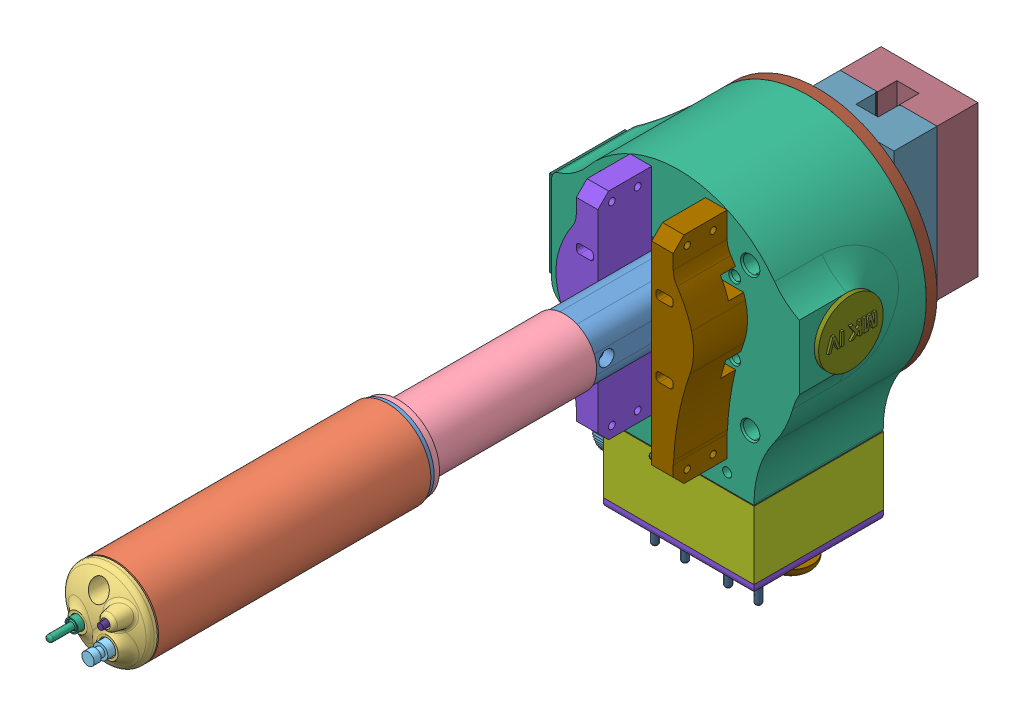
SolidWorks assembly simple_collective, configuration По умолчанию. Lengths in mm.
Overall size (184.78 180.53 404.93).
48 component instances, 32 part files, 9 mates.
Components (placement in the parent):
- collective_base-1: collective_base [По умолчанию] at origin size (122 120.43 169.5)
  - collective_base_lever_connector_cbase010-1: collective_base_lever_connector_cbase010 [По умолчанию] at (44.3103 52.5722 -4.4772) size (25 25 86)
  - 608_bearing_v1-1: 608_bearing_v1 [По умолчанию] at (58.4103 52.5722 5.5228) x (0 -0.975622 0.219457) z (0 0.219457 0.975622) size (22 7.15 22)
  - 608_bearing_v1-2: 608_bearing_v1 [По умолчанию] at (16.3103 52.5722 5.5228) x (0 -1 0) z (0 0 1) size (22 7.15 22)
  - 608_bearing_v1-3: 608_bearing_v1 [По умолчанию] at (72.3103 52.5722 5.5228) x (0 1 0) z (0 0 1) size (22 7.15 22)
  - 608_bearing_v1-4: 608_bearing_v1 [По умолчанию] at (30.2103 52.5722 5.5228) x (0 1 0) z (0 0 1) size (22 7.15 22)
  - M8 washer_regular-1: M8 washer_regular [По умолчанию] at (31.8103 52.5722 5.5228) x (0 0 1) z (-1 0 0) size (15.8 15.8 1.5)
  - M8 washer_regular-2: M8 washer_regular [По умолчанию] at (58.3103 52.5722 5.5228) x (0 0 1) z (-1 0 0) size (15.8 15.8 1.5)
  - collective_base_hinge_frame_p1_cbase007-3: collective_base_hinge_frame_p1_cbase007 [По умолчанию] at (44.3103 52.5722 20.5228) x (1 0 0) z (0 1 0) size (78.5 15 68)
  - M6x70mm-1: M6x70mm [По умолчанию] at (5.4103 52.5722 5.5228) x (0 -0.980406 -0.196989) z (0 -0.196989 0.980406) size (11.6 74.3 11.6)
  - collective_base_housing_p1_cbase001-1: collective_base_housing_p1_cbase001 [По умолчанию] at (44.3103 44.0722 -32.4772) x (0 1 0) z (1 0 0) size (117.43 62.91 115.35)
  - collective_base_hinge_frame_p2_cbase008-2: collective_base_hinge_frame_p2_cbase008 [По умолчанию] at (44.3103 52.5722 -9.4772) x (-1 0 0) z (0 1 0) size (65 15 68)
  - collective_base_friction_tensioner_p2_cbase012-1: collective_base_friction_tensioner_p2_cbase012 [По умолчанию] at (21.8103 44.2222 27.5228) x (1 0 0) z (0 -1 0) size (19.47 25 100)
  - collective_base_friction_tensioner_p1_cbase011-1: collective_base_friction_tensioner_p1_cbase011 [По умолчанию] at (66.8103 44.1222 52.5228) x (-1 0 0) z (0 -1 0) size (19.47 25 100)
  - 6x6x4mm_square-1: 6x6x4mm_square [По умолчанию] at (2.4103 49.5722 5.5228) size (6 6 4)
  - M8 washer_regular-3: M8 washer_regular [По умолчанию] at (72.4103 52.5722 5.5228) x (0 0 -1) z (1 0 0) size (15.8 15.8 1.5)
  - M8 washer_regular-4: M8 washer_regular [По умолчанию] at (75.4103 52.5722 5.5228) x (0 0 1) z (-1 0 0) size (15.8 15.8 1.5)
  - collective_base_housing_p2_cbase002-1: collective_base_housing_p2_cbase002 [По умолчанию] at (44.3103 44.0722 -37.4772) x (0 -1 0) z (-1 0 0) size (110 22.5 110)
  - collective_base_hinge_curtain_cbase009-1: collective_base_hinge_curtain_cbase009 [По умолчанию] at (42.9159 43.7468 -9.4772) x (1 0 0) z (0 0 -1) size (65 54.8 2.4)
  - collective_base_housing_p4_cbase004-1: collective_base_housing_p4_cbase004 [По умолчанию] at (44.3103 44.0722 -88.9772) x (-1 0 0) z (0 1 0) size (45 19 70)
  - collective_base_housing_p3_cbase003-1: collective_base_housing_p3_cbase003 [По умолчанию] at (44.3103 44.0722 -49.9772) x (1 0 0) z (0 1 0) size (45 20 70)
  - collective_base_housing_p5_cbase005-1: collective_base_housing_p5_cbase005 [По умолчанию] at (-10.6795 48.8722 6.7228) x (0 0 -1) z (0 1 0) size (39 8 44)
  - collective_base_housing_p6_cbase006-1: collective_base_housing_p6_cbase006 [По умолчанию] at (96.3205 51.5722 5.5228) x (0 0.9998 0.019984) z (0 0.019984 -0.9998) size (32 7 32)
  - 6x17mm_tact-1: 6x17mm_tact [По умолчанию] at (44.3103 1.0722 -29.5772) x (1 0 0) z (0 0 -1) size (5.8 5.8 16.4)
  - collective_base_pedestal_mockup_cbase013-1: collective_base_pedestal_mockup_cbase013 [По умолчанию] at (44.3103 -18.3542 -2.4772) x (1 0 0) z (0 -1 0) size (72 62 7)
- simple_collective_body-1: simple_collective_body [По умолчанию] at (115.5739 187.1995 -54.6178) x (0.899263 0.322697 -0.295284) z (0.337757 -0.941233 0) size (114.48 229.77 53.21)
  - simple_collective_throttle_frame_part1_slbody02-1: simple_collective_throttle_frame_part1_slbody02 [По умолчанию] at (-187.9177 226.7631 102.661) x (0.322697 0.099734 -0.941233) z (-0.899263 -0.277931 -0.337757) size (39 92 39)
  - simple_collective_throttle_grip_slbody04-1: simple_collective_throttle_grip_slbody04 [По умолчанию] at (-171.6771 174.2155 102.661) x (-0.941612 -0.291019 -0.169335) z (-0.295284 0.95541 0) size (40 40 126.4)
  - simple_collective_throttle_frame_part2_slbody03-1: simple_collective_throttle_frame_part2_slbody03 [По умолчанию] at (-192.3469 241.0942 102.661) x (-0.899263 -0.277931 -0.337757) z (-0.295284 0.95541 0) size (41.6 41.6 71)
  - simple_lever_body_decorative_casing_slbody01-2: simple_lever_body_decorative_casing_slbody01 [По умолчанию] at (-147.4638 95.872 102.661) x (0.322697 0.099734 -0.941233) z (0.899263 0.277931 0.337757) size (38 80 38)
  - PBS10-B2-1: PBS10-B2 [По умолчанию] at (-204.7847 295.8637 110.8404) x (0.95541 0.295284 0) z (0 0 1) size (9.4 20 9.4)
  - 6x17mm_tact-1: 6x17mm_tact [По умолчанию] at (-197.9561 299.1256 99.4499) x (0.899263 0.277931 0.337757) z (-0.295284 0.95541 0) size (5.8 5.8 16.4)
  - MTS-223-A2-1: MTS-223-A2 [По умолчанию] at (-214.817 288.0531 103.1204) x (0.322697 0.099734 -0.941233) z (0.899263 0.277931 0.337757) size (13.2 33.3 12.7)
- simple_pedestal-1: simple_pedestal [По умолчанию] at (44.3389 -6.7542 -2.4772) x (1 0 0) z (0 -1 0) size (85.5 63.6 66.5)
  - simple_pedestal_panel_housing_spdstl01-1: simple_pedestal_panel_housing_spdstl01 [По умолчанию] at origin size (70 60 43.5)
  - simple_pedestal_panel_spdstl02-1: simple_pedestal_panel_spdstl02 [По умолчанию] at (0 0 43.5) size (73.6 63.6 8)
  - KY-083-1: KY-083 [По умолчанию] at (14 -9.5 30) x (0 -1 0) z (-1 0 0) size (27.6 34.3 38.4)
  - MTS-103-1: MTS-103 [По умолчанию] at (-24 17 34) x (0 -1 0) z (-1 0 0) size (13.2 33.3 7.9)
  - MTS-103-2: MTS-103 [По умолчанию] at (24 17 34) x (0 1 0) z (1 0 0) size (13.2 33.3 7.9)
  - MTS-103-3: MTS-103 [По умолчанию] at (10 17 34) x (0 1 0) z (1 0 0) size (13.2 33.3 7.9)
  - MTS-103-4: MTS-103 [По умолчанию] at (-10 17 34) x (0 1 0) z (1 0 0) size (13.2 33.3 7.9)
  - PBS10-B2-1: PBS10-B2 [По умолчанию] at (-8 5 35.5) x (1 0 0) z (0 -1 0) size (9.4 20 9.4)
  - PBS10-B2-2: PBS10-B2 [По умолчанию] at (-8 -21 35.5) x (1 0 0) z (0 -1 0) size (9.4 20 9.4)
  - PEC16-4220F-S0024-3: PEC16-4220F-S0024 [По умолчанию] at (-23 -8 37.9) x (0 1 0) z (1 0 0) size (20.3 25.6 16.3)
  - simple_pedestal_mousewheel_knob_spdstl04-2: simple_pedestal_mousewheel_knob_spdstl04 [По умолчанию] at (-23 -8 48.5) x (1 0 0) z (0 -1 0) size (15 18 15)
  - PTD901-2015K-B103-1: PTD901-2015K-B103 [По умолчанию] at (-26 5 25) x (0 1 0) z (0 0 1) size (9.6 21.7 11.3)
  - simple_pedestal_zoom_axis_knob_spdstl03-1: simple_pedestal_zoom_axis_knob_spdstl03 [По умолчанию] at (-35.7 5 25) x (0 0.999916 -0.012992) z (0 0.012992 0.999916) size (35 13 40)
- MTS-103-1: MTS-103 [По умолчанию] at (44.3103 -10.3542 11.0228) x (1 0 0) z (0 -1 0) size (13.2 33.3 7.9)
Mates (geometry in assembly coordinates):
- Coincident1: coincident aligned: plane of collective_base-1/collective_base_lever_connector_cbase010-1 through (49.4353 57.6972 80.5228) normal (0 -1 0); plane of simple_collective_body-1/simple_lever_body_decorative_casing_slbody01-2 through (49.4353 57.6972 160.5228) normal (0 -1 0)
- Coincident2: coincident aligned: plane of collective_base-1/collective_base_lever_connector_cbase010-1 through (49.4353 47.4472 80.5228) normal (-1 0 0); plane of simple_collective_body-1/simple_lever_body_decorative_casing_slbody01-2 through (49.4353 57.6972 160.5228) normal (-1 0 0)
- Coincident3: coincident anti-aligned: plane of collective_base-1/collective_base_lever_connector_cbase010-1 through (44.3103 52.5722 80.5228) normal (0 0 1); plane of simple_collective_body-1/simple_lever_body_decorative_casing_slbody01-2 through (44.2853 52.5472 80.5228) normal (0 0 -1)
- Concentric3: concentric aligned: cylinder of collective_base-1/collective_base_housing_p1_cbase001-1 through (21.8389 -11.3542 -35.3866) axis (0 0 1) radius 2.1; cylinder of simple_pedestal-1/simple_pedestal_panel_housing_spdstl01-1 through (21.8389 -11.3542 -32.4772) axis (0 0 1) radius 2.1
- Parallel4: parallel aligned: line of collective_base-1/collective_base_housing_p1_cbase001-1 through (79.3103 -18.3542 27.5228) axis (-1 0 0); line of simple_pedestal-1/simple_pedestal_panel_housing_spdstl01-1 through (79.3389 -18.7542 27.5228) axis (-1 0 0)
- Coincident14: coincident aligned: plane of collective_base-1/collective_base_housing_p1_cbase001-1 through (44.3103 44.0722 27.5228) normal (0 0 1); plane of simple_pedestal-1/simple_pedestal_panel_housing_spdstl01-1 through (79.3389 -50.2542 27.5228) normal (0 0 1)
- Concentric4: concentric anti-aligned: cylinder of collective_base-1/collective_base_housing_p1_cbase001-1 through (44.3103 -10.3542 8.4718) axis (0 0 1) radius 3.2; cylinder of MTS-103-1 through (44.3103 -10.3542 29.3228) axis (0 0 -1) radius 3
- Coincident15: coincident anti-aligned: plane of collective_base-1/collective_base_housing_p1_cbase001-1 through (44.3103 44.0722 20.5228) normal (0 0 -1); plane of MTS-103-1 through (44.3103 -10.3542 20.5228) normal (0 0 1)
- Parallel5: parallel aligned: line of collective_base-1/collective_base_housing_p1_cbase001-1 through (51.3103 -5.8542 17.5228) axis (-1 0 0); line of MTS-103-1 through (50.9103 -6.4042 11.0228) axis (-1 0 0)
